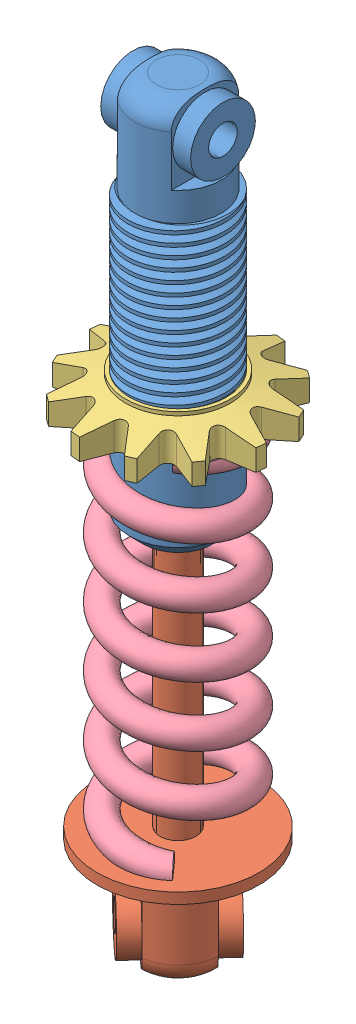
SolidWorks assembly shock absorber, configuration Default. Lengths in mm.
Overall size (65.69 213.4 65.69).
4 component instances, 4 part files, 7 mates.
Components (placement in the parent):
- top rod-1: top rod [Default] at (40.6966 -0.8943 86.2632) size (28.39 109.38 27.01)
- base of shock absorber-1: base of shock absorber [Default] at (40.6966 -76.4544 86.2632) x (-0.674269 0 0.738486) z (-0.738486 0 -0.674269) size (45 101.45 45)
- nut-1: nut [Default] at (40.6966 26.5456 86.2632) x (-0.933606 0 -0.358303) z (0.358303 0 -0.933606) size (50.85 11.87 50.85)
- spring-1: spring [Default] at (40.6966 26.5456 86.2632) x (0.665412 0 0.746476) z (-0.746476 0 0.665412) size (38.29 107.15 37.25)
Mates (geometry in assembly coordinates):
- Concentric1: concentric aligned: cylinder of top rod-1 through (40.6966 74.1057 86.2632) axis (0 -1 0) radius 5; cylinder of base of shock absorber-1 through (40.6966 -3.4544 86.2632) axis (0 -1 0) radius 5
- Concentric2: concentric aligned: cylinder of top rod-1 through (40.6966 108.0357 86.2632) axis (0 -1 0) radius 12; cylinder of nut-1 through (40.6966 36.5456 86.2632) axis (0 -1 0) radius 14.5
- Screw1: screw = 1 aligned: line of top rod-1 through (40.6966 80.0357 86.2632) axis (0 -1 0); cylinder of nut-1 through (40.6966 36.5456 86.2632) axis (0 -1 0) radius 14.5
- Coincident2: coincident anti-aligned: plane of nut-1 through (40.6966 26.5456 86.2632) normal (0 -1 0); plane of spring-1 through (40.6966 26.5456 86.2632) normal (0 1 0)
- Coincident5: coincident aligned: line of base of shock absorber-1 through (40.6966 -3.4544 86.2632) axis (0 -1 0); line of spring-1 through (40.6966 26.5456 86.2632) axis (0 -1 0)
- Concentric3: concentric aligned: cylinder of nut-1 through (40.6966 36.5456 86.2632) axis (0 -1 0) radius 14.5; line of spring-1 through (40.6966 26.5456 86.2632) axis (0 -1 0)
- Coincident7: coincident anti-aligned: plane of base of shock absorber-1 through (40.6966 -73.4544 86.2632) normal (0 1 0); plane of spring-1 through (40.6966 -73.4544 86.2632) normal (0 -1 0)
